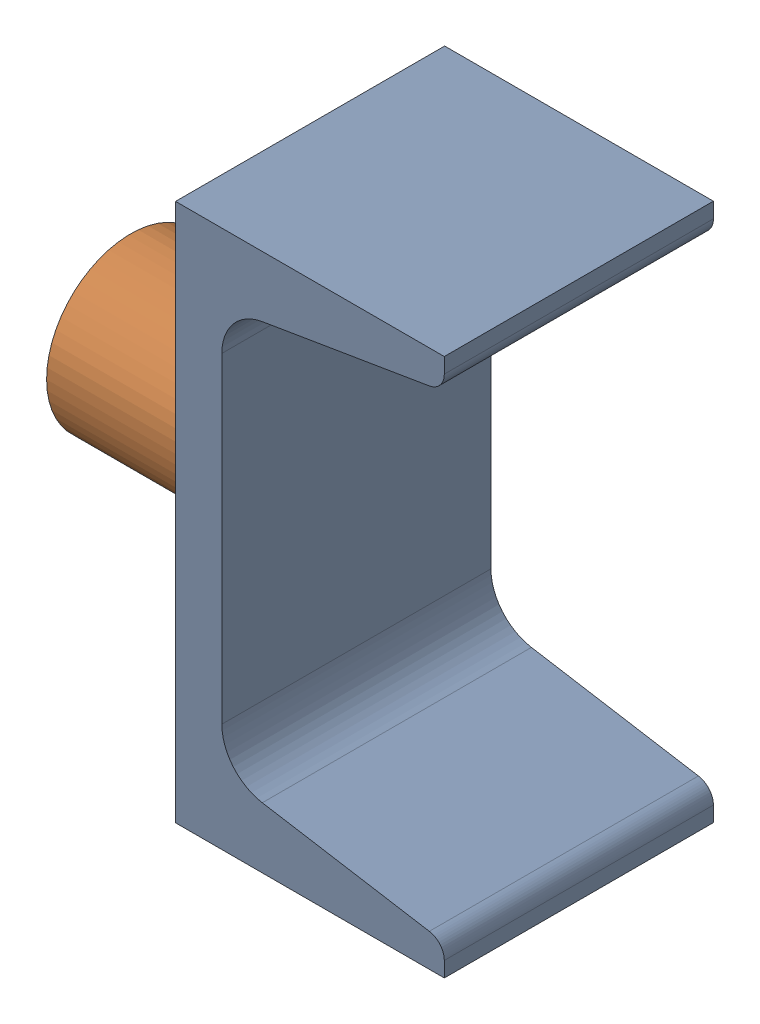
SolidWorks assembly 01-113-00-0, configuration Default. Lengths in mm.
Overall size (63.45 76.2 38.1).
2 component instances, 2 part files, 3 mates.
Components (placement in the parent):
- 01-112-00-0-1: 01-112-00-0 [Default] at (-117.0124 -34.5535 49.2974) size (38.05 76.2 38.1)
- 01-111-00-0-1: 01-111-00-0 [Default] at (-142.4124 3.5465 49.2974) x (0 -1 0) z (0 0 1) size (23.81 25.4 23.81)
Mates (geometry in assembly coordinates):
- Coincident1: coincident anti-aligned: plane of 01-112-00-0-1 through (-117.0124 -34.5535 68.3474) normal (-1 0 0); plane of 01-111-00-0-1 through (-117.0124 3.5465 49.2974) normal (1 0 0)
- Distance2: distance = 38.1 mm: moEndPointRef_w of 01-111-00-0-1; plane of 01-112-00-0-1 through (-117.0124 41.6465 68.3474) normal (0 1 0)
- Distance3: distance = 19.05 mm: moEndPointRef_w of 01-111-00-0-1; plane of 01-112-00-0-1 through (-81.5032 -32.3958 30.2474) normal (0 0 -1)
